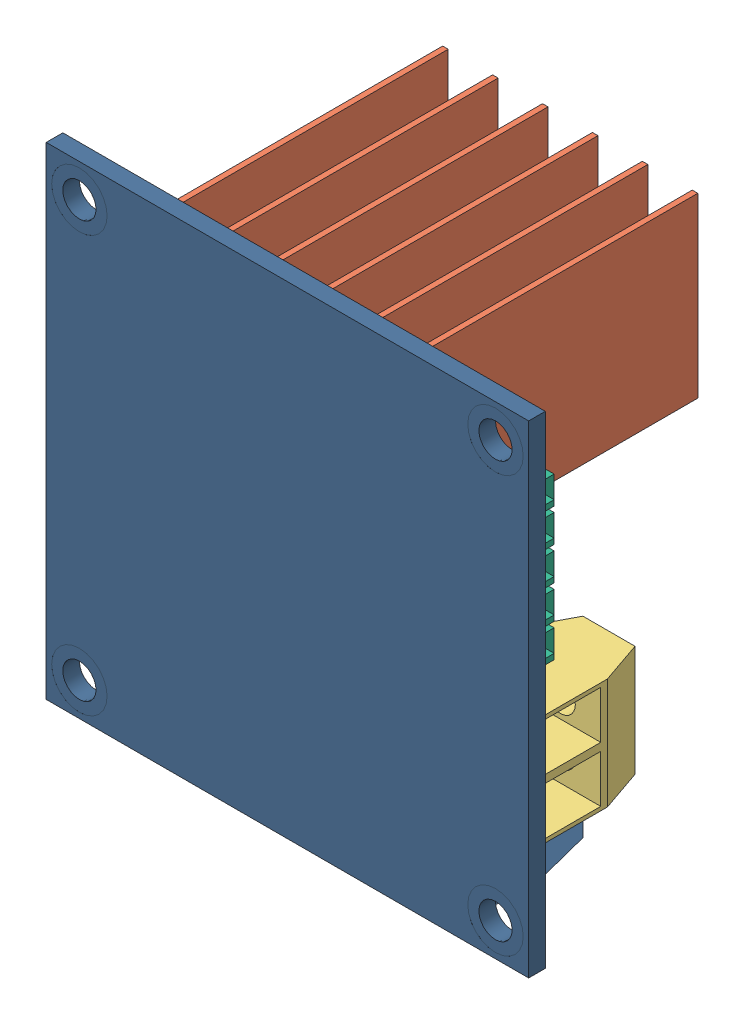
SolidWorks assembly Assem1 (H_Bridg motor drive L298N), configuration Default. Lengths in mm.
Overall size (43.5 43.5 25.5).
22 component instances, 11 part files, 32 mates.
Components (placement in the parent):
- Screw terminal 3 way-1: Screw terminal 3 way [Default] at (-28.9718 33.8284 6.6889) x (0 -1 0) z (1 0 0) size (8 10 15)
- HEIT SINK-1: HEIT SINK [Default] at (-29.1218 64.4316 -17.3111) size (23 16 24)
- Screw terminal 2 way-1: Screw terminal 2 way [Default] at (-45.687 48.2316 6.6889) x (-1 0 0) z (0 -1 0) size (8 10 10)
- Capacitor-1: Capacitor [Default] at (-22.8218 46.5816 6.6889) x (-1 0 0) z (0 0 -1) size (8.3 8.3 9.3)
- Dual pin header-1: Dual pin header [Default] at (-19.9381 40.9757 6.6889) x (1 0 0) z (0 0 -1) size (5 2.54 9.8)
- Diode-1: Diode [Default] at (-47.1718 53.5316 5.4389) x (-1 0 0) z (0 -1 0) size (6 3 2.5)
- Pin header-1: Pin header [Default] at (-29.8134 30.9296 6.6889) x (-1 0 0) z (0 0 -1) size (15.26 5 8.5)
- Regulator-1: Regulator [Default] at (-35.3718 48.2816 6.6889) x (0 -1 0) z (0 0 -1) size (6.9 12.43 2.3)
- L298N-1: L298N [Default] at (-28.3253 63.4316 -7.8089) x (-1 0 0) z (0 -1 0) size (20.12 22.39 9.32)
- BCP-3: BCP [Default] at (-29.1218 50.7816 8.1889) x (0 1 0) z (0 0 -1) size (43.5 43.5 1.5)
- Capacitor-2: Capacitor [Default] at (-35.8218 39.6816 6.6889) x (-1 0 0) z (0 0 -1) size (8.3 8.3 9.3)
- Diode-3: Diode [Default] at (-47.1718 56.5316 5.4389) x (-1 0 0) z (0 -1 0) size (6 3 2.5)
- Diode-9: Diode [Default] at (-47.1718 59.5316 5.4389) x (-1 0 0) z (0 -1 0) size (6 3 2.5)
- Diode-11: Diode [Default] at (-47.1718 62.5316 5.4389) x (-1 0 0) z (0 -1 0) size (6 3 2.5)
- Diode-13: Diode [Default] at (-47.1718 65.5316 5.4389) x (-1 0 0) z (0 -1 0) size (6 3 2.5)
- Diode-15: Diode [Default] at (-11.0718 53.5316 5.4389) x (-1 0 0) z (0 -1 0) size (6 3 2.5)
- Diode-8: Diode [Default] at (-11.0718 56.5316 5.4389) x (-1 0 0) z (0 -1 0) size (6 3 2.5)
- Diode-10: Diode [Default] at (-11.0718 59.5316 5.4389) x (-1 0 0) z (0 -1 0) size (6 3 2.5)
- Diode-12: Diode [Default] at (-11.0718 62.5316 5.4389) x (-1 0 0) z (0 -1 0) size (6 3 2.5)
- Diode-14: Diode [Default] at (-11.0718 65.5316 5.4389) x (-1 0 0) z (0 -1 0) size (6 3 2.5)
- Screw terminal 2 way-3: Screw terminal 2 way [Default] at (-12.5566 38.2316 6.6889) x (1 0 0) z (0 1 0) size (8 10 10)
- pan head cross recess screw_din-1: pan head cross recess screw_din [DIN EN ISO 7045 - M3 x 6 - Z - 6S] at (-29.1218 59.4316 -11.3111) x (0 1 0) z (0 0 1) size (8.35 5.6 5.6)
Mates (geometry in assembly coordinates):
- Coincident6: coincident anti-aligned: plane of Part2-1 through (-29.1218 64.4316 6.6889) normal (0 0 1); plane of Part1-3 through (-29.1218 50.7816 6.689) normal (0 0 -1)
- Coincident7: coincident aligned: line of Part2-1 through (-17.6218 72.4316 6.6889) axis (0 -1 0); line of Part1-3 through (-17.6218 72.4316 6.6889) axis (0 -1 0)
- Coincident8: coincident anti-aligned: line of Part2-1 through (-18.1218 72.4316 6.6889) axis (1 0 0); line of Part1-3 through (-17.6218 72.4316 6.6889) axis (-1 0 0)
- Coincident14: coincident anti-aligned: plane of Part2-1 through (-29.1218 63.4316 6.6889) normal (0 -1 0); plane of L298N-1 through (-28.3253 63.4316 -7.8089) normal (0 1 0)
- Coincident17: coincident anti-aligned: circle of Part2-1; cylinder of L298N-1 through (-29.1218 61.8316 -11.3111) axis (0 1 0) radius 1.5
- Parallel2: parallel aligned: plane of L298N-1 through (-37.8968 55.0118 5.4142) normal (-1 0 0); plane of Part1-3 through (-50.8718 72.5316 6.6889) normal (-1 0 0)
- Coincident19: coincident anti-aligned: plane of Part36-1 through (-22.8218 46.5816 6.6889) normal (0 0 1); plane of Part1-3 through (-29.1218 50.7816 6.689) normal (0 0 -1)
- Coincident22: coincident aligned: line of Part36-1 through (-18.6718 48.5616 6.6889) axis (0 -1 0); line of Part1-3 through (-18.6718 48.2616 6.6889) axis (0 -1 0)
- Coincident23: coincident aligned: line of Part36-1 through (-26.9718 50.7316 6.6889) axis (1 0 0); line of Part1-3 through (-26.9718 50.7316 6.6889) axis (1 0 0)
- Coincident24: coincident aligned: line of Part1-3 through (-31.6718 41.3616 6.6889) axis (0 -1 0); line of Part36-2 through (-31.6718 41.6616 6.6889) axis (0 -1 0)
- Coincident26: coincident aligned: line of Part1-3 through (-34.1418 35.5316 6.6889) axis (-1 0 0); line of Part36-2 through (-33.8418 35.5316 6.6889) axis (-1 0 0)
- Coincident27: coincident anti-aligned: plane of Part3-1 through (-42.2718 38.2316 6.6889) normal (0 0 1); plane of Part1-3 through (-29.1218 50.7816 6.689) normal (0 0 -1)
- Coincident28: coincident aligned: line of Part3-1 through (-50.2718 38.2316 6.6889) axis (0 1 0); line of Part1-3 through (-50.2718 38.2316 6.6889) axis (0 1 0)
- Coincident29: coincident aligned: line of Part3-1 through (-42.2718 38.2316 6.6889) axis (-1 0 0); line of Part1-3 through (-42.2718 38.2316 6.6889) axis (-1 0 0)
- Coincident30: coincident anti-aligned: plane of Part166-1 through (-13.9718 37.6316 6.6889) normal (0 0 1); plane of Part1-3 through (-29.1218 50.7816 6.689) normal (0 0 -1)
- Coincident31: coincident: point of Part166-1; point of Part1-3
- Coincident32: coincident: point of Part166-1; point of Part1-3
- Coincident35: coincident anti-aligned: plane of Part377-1 through (-19.9381 40.9757 6.6889) normal (0 0 1); plane of Part1-3 through (-29.1218 50.7816 6.689) normal (0 0 -1)
- Coincident36: coincident aligned: line of Part377-1 through (-22.3718 38.9357 6.6889) axis (0 1 0); line of Part1-3 through (-22.3718 39.1416 6.6889) axis (0 1 0)
- Coincident37: coincident aligned: line of Part377-1 through (-17.8718 38.4316 6.6889) axis (-1 0 0); line of Part1-3 through (-18.0818 38.4316 6.6889) axis (-1 0 0)
- Coincident38: coincident aligned: line of Part47-1 through (-45.0718 30.9356 6.6889) axis (0 1 0); line of Part1-3 through (-45.0718 30.4316 6.6889) axis (0 1 0)
- Coincident39: coincident aligned: line of Part47-1 through (-44.5718 35.4316 6.6889) axis (1 0 0); line of Part1-3 through (-45.0718 35.4316 6.6889) axis (1 0 0)
- Coincident54: coincident aligned: line of Part4-1 through (-49.1718 51.0316 6.6889) axis (0 1 0); line of Part1-3 through (-49.1718 51.0316 6.6889) axis (0 1 0)
- Coincident55: coincident aligned: line of Part4-1 through (-45.1718 51.0316 6.6889) axis (-1 0 0); line of Part1-3 through (-45.1718 51.0316 6.6889) axis (-1 0 0)
- Coincident56: coincident aligned: line of Part5-1 through (-39.8718 44.8316 6.6889) axis (0 1 0); line of Part1-3 through (-39.8718 44.8316 6.6889) axis (0 1 0)
- Coincident57: coincident: plane of Part5-1 through (-30.8718 51.7316 4.3889) normal (0 1 0); line of Part1-3 through (-39.8718 51.7316 6.6889) axis (1 0 0)
- Coincident59: coincident anti-aligned: plane of Part5-1 through (-35.3718 48.2816 6.6889) normal (0 0 1); plane of Part1-3 through (-29.1218 50.7816 6.689) normal (0 0 -1)
- Coincident60: coincident anti-aligned: line of Part1-3 through (-7.9718 38.2316 6.6889) axis (-1 0 0); line of Part3-3 through (-15.9718 38.2316 6.6889) axis (1 0 0)
- Coincident61: coincident: line of Part1-3 through (-7.9718 48.2316 6.6889) axis (0 -1 0); plane of Part3-3 through (-7.9718 48.2316 6.6889) normal (1 0 0)
- Coincident62: coincident anti-aligned: plane of Part1-3 through (-29.1218 50.7816 6.689) normal (0 0 -1); plane of Part3-3 through (-15.9718 48.2316 6.6889) normal (0 0 1)
- Concentric1: concentric anti-aligned: cylinder of L298N-1 through (-29.1218 61.8316 -11.3111) axis (0 1 0) radius 1.5; cylinder of pan head cross recess screw_din-1 through (-29.1218 34.0316 -11.3111) axis (0 -1 0) radius 1.5
- Coincident63: coincident anti-aligned: plane of L298N-1 through (-28.3253 61.8316 -7.8089) normal (0 -1 0); plane of pan head cross recess screw_din-1 through (-30.6218 61.8316 -11.3111) normal (0 1 0)
